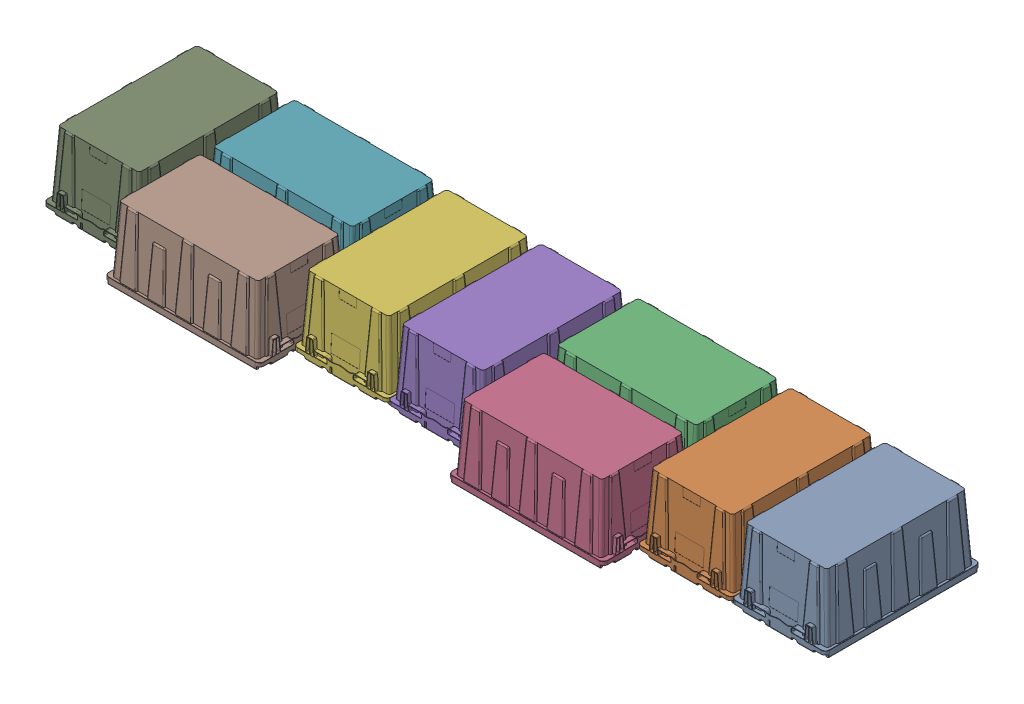
SolidWorks assembly LANDFILL_GP3_ASM, configuration Default. Lengths in mm.
Overall size (3422.65 313.83 831.85).
9 component instances, 1 part files, 0 mates.
Components (placement in the parent):
- GRAY_TOTE-1: GRAY_TOTE [Default] at (0 311.15 0) x (0 -1 0) z (0 0 1) size (313.83 412.75 692.15)
- GRAY_TOTE-2: GRAY_TOTE [Default] at (-412.75 311.15 0) x (0 -1 0) z (0 0 1) size (313.83 412.75 692.15)
- GRAY_TOTE-3: GRAY_TOTE [Default] at (-958.85 311.15 -133.35) x (0 -1 0) z (1 0 0) size (313.83 412.75 692.15)
- GRAY_TOTE-4: GRAY_TOTE [Default] at (-958.85 311.15 279.4) x (0 -1 0) z (1 0 0) size (313.83 412.75 692.15)
- GRAY_TOTE-5: GRAY_TOTE [Default] at (-1504.95 311.15 0) x (0 -1 0) z (0 0 -1) size (313.83 412.75 692.15)
- GRAY_TOTE-6: GRAY_TOTE [Default] at (-1917.7 311.15 0) x (0 -1 0) z (0 0 -1) size (313.83 412.75 692.15)
- GRAY_TOTE-7: GRAY_TOTE [Default] at (-2463.8 311.15 -133.35) x (0 -1 0) z (1 0 0) size (313.83 412.75 692.15)
- GRAY_TOTE-8: GRAY_TOTE [Default] at (-2463.8 311.15 279.4) x (0 -1 0) z (1 0 0) size (313.83 412.75 692.15)
- GRAY_TOTE-9: GRAY_TOTE [Default] at (-3009.9 311.15 0) x (0 -1 0) z (0 0 -1) size (313.83 412.75 692.15)
